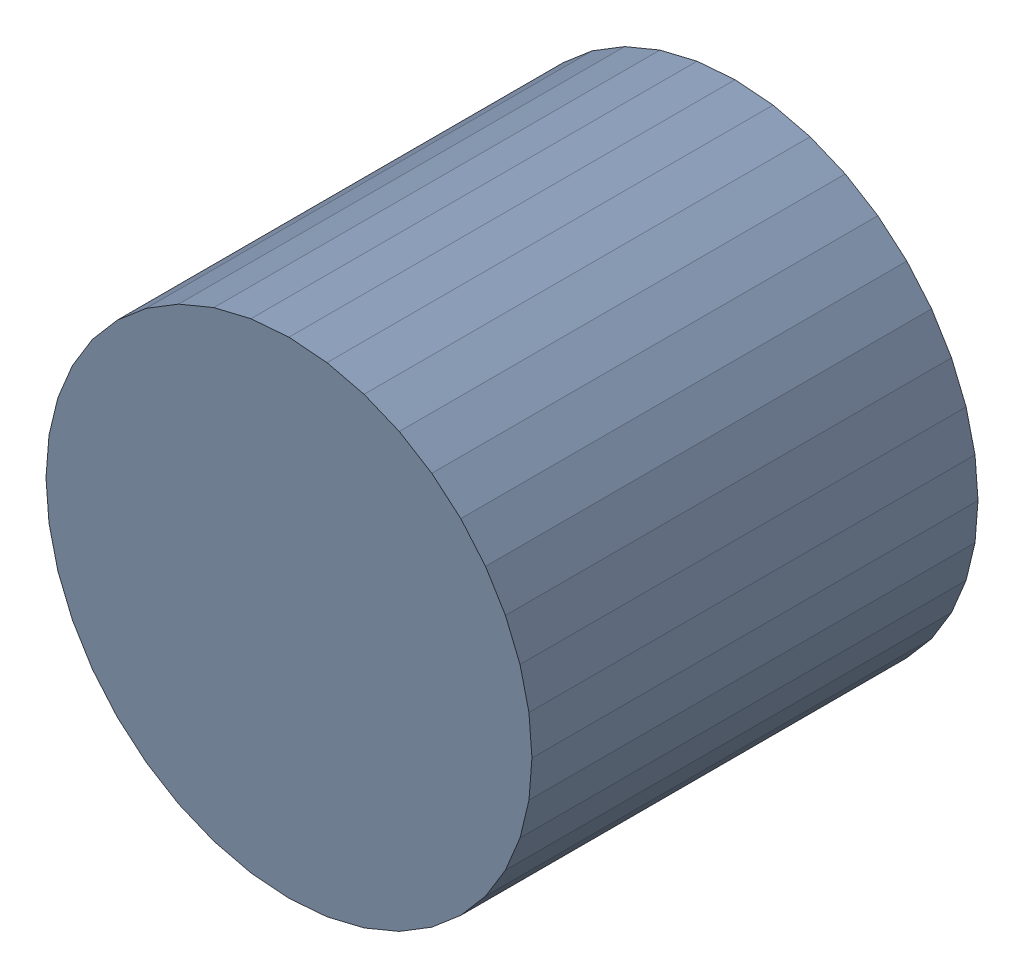
SolidWorks assembly USB01_C5, configuration Default. Lengths in mm.
Overall size (6.32 6.32 5.8).
2 component instances, 1 part files, 0 mates.
Components (placement in the parent):
- 384312384-1: 384312384 [Default] at (149.86 69.723 -6.9024) size (6.32 6.32 5.8)
  - Extruded_7-1: Extruded_7 [Default] at origin size (6.32 6.32 5.8)
